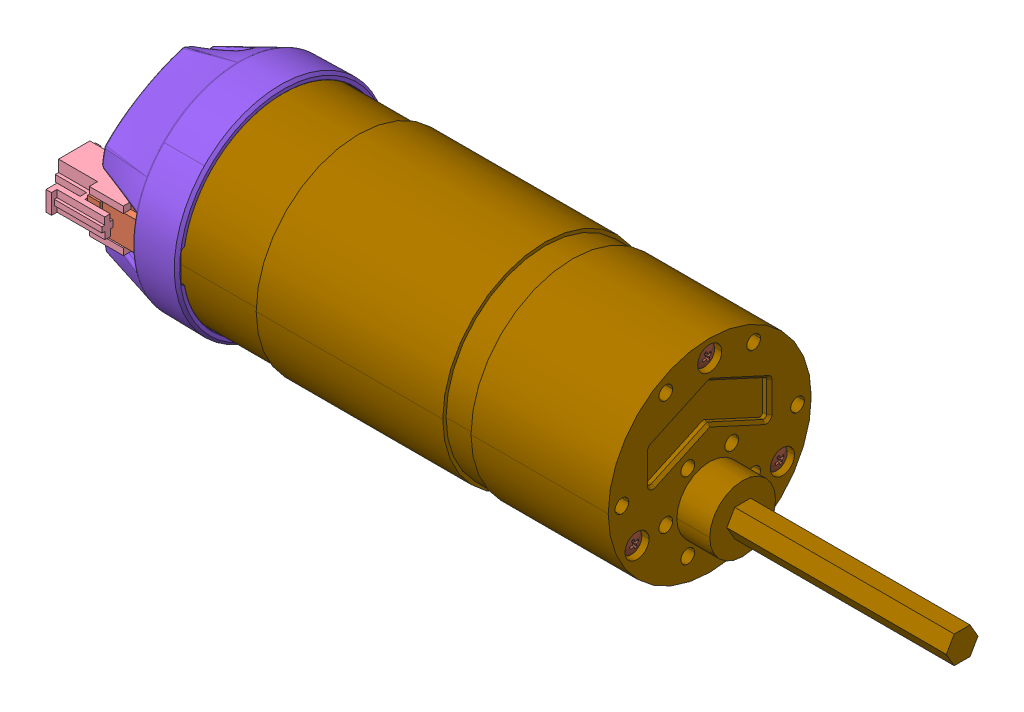
SolidWorks assembly REV-41-1301, configuration Default. Lengths in mm.
Overall size (148.2 61.13 58.82).
16 component instances, 11 part files, 0 mates.
Components (placement in the parent):
- REV-41-1301.STEP-1: REV-41-1301.STEP [Default] at origin size (148.2 61.13 58.82)
  - HD Hex PCB assembly.STEP-1: HD Hex PCB assembly.STEP [Default] at (19.3182 25.1059 5.8173) x (0 -0.71934 0.694658) z (0 -0.694658 -0.71934) size (33.74 20.2 32.49)
    - HD Hex PCB.STEP-1: HD Hex PCB.STEP [Default] at (-2.7819 22.0182 36.8752) size (33.6 1 30.5)
    - JST-B2P-VH.STEP-1: JST-B2P-VH.STEP [Default] at (22.7477 23.0182 9.8272) x (0.716277 0 0.697816) z (0 1 0) size (7.86 8.5 14.6)
    - JST-B4B-PH-K-S.STEP-1: JST-B4B-PH-K-S.STEP [Default] at (2.3468 23.0182 29.0038) x (-0.707107 0 -0.707107) z (0 1 0) size (9.9 4.5 9.4)
    - JST-VHR-2N.STEP-1: JST-VHR-2N.STEP [Default] at (21.5142 32.8682 13.9307) x (-0.716277 0 -0.697816) z (0 -1 0) size (7.86 10.5 13.3)
    - JST-PHR-4.STEP-1: JST-PHR-4.STEP [Default] at (0.4906 28.1932 31.9206) x (-0.707107 0 -0.707107) z (0 -1 0) size (9.8 4.5 6.85)
  - HD Hex Encoder Baseplate.STEP-1: HD Hex Encoder Baseplate.STEP [Default] at (1.3 0 0) x (0 -0.716644 0.697439) z (0 -0.697439 -0.716644) size (39.9 7.52 38.17)
  - magnet.STEP-1: magnet.STEP [Default] at (-11.2 0 0) x (0 -0.958456 0.28524) z (0 0.28524 0.958456) size (14 5.5 14)
  - HD Hex Encoder Case Top.STEP-1: HD Hex Encoder Case Top.STEP [Default] at (-3.7 0 0) x (0 -0.716302 0.69779) z (0 -0.69779 -0.716302) size (44.21 20.13 38.77)
  - Motor dummy.STEP-1: Motor dummy.STEP [Default] x (1 0 0) z (0 0 -1) size (140.7 37.3 37.3)
  - 90190A051_PAN HEAD PHILLIPS SCREW FOR SHEET METAL_90190A051.STEP-1: 90190A051_PAN HEAD PHILLIPS SCREW FOR SHEET METAL_90190A051.STEP [Default] at (-6.7 -15.0231 3.8154) x (0 0.99946 0.032862) z (-1 0 0) size (3.48 2.95 7.69)
  - 90190A051_PAN HEAD PHILLIPS SCREW FOR SHEET METAL_90190A051.STEP-2: 90190A051_PAN HEAD PHILLIPS SCREW FOR SHEET METAL_90190A051.STEP [Default] at (-6.7 15.0231 -3.8154) x (0 1 0) z (-1 0 0) size (3.48 2.95 7.69)
  - pan cross head_am_B18.6.7M - M2 x 0.4 x 2.5 Type I Cross Recessed PHMS --2.5N.STEP-1: pan cross head_am_B18.6.7M - M2 x 0.4 x 2.5 Type I Cross Recessed PHMS --2.5N.STEP [Default] at (81.6 15.2998 0) x (-1 0 0) z (0 0.924225 0.381849) size (4.08 4 4)
  - pan cross head_am_B18.6.7M - M2 x 0.4 x 2.5 Type I Cross Recessed PHMS --2.5N.STEP-2: pan cross head_am_B18.6.7M - M2 x 0.4 x 2.5 Type I Cross Recessed PHMS --2.5N.STEP [Default] at (81.6 -7.6499 13.25) x (-1 0 0) z (0 0.924225 0.381849) size (4.08 4 4)
  - pan cross head_am_B18.6.7M - M2 x 0.4 x 2.5 Type I Cross Recessed PHMS --2.5N.STEP-3: pan cross head_am_B18.6.7M - M2 x 0.4 x 2.5 Type I Cross Recessed PHMS --2.5N.STEP [Default] at (81.6 -7.6499 -13.25) x (-1 0 0) z (0 0.924225 0.381849) size (4.08 4 4)
